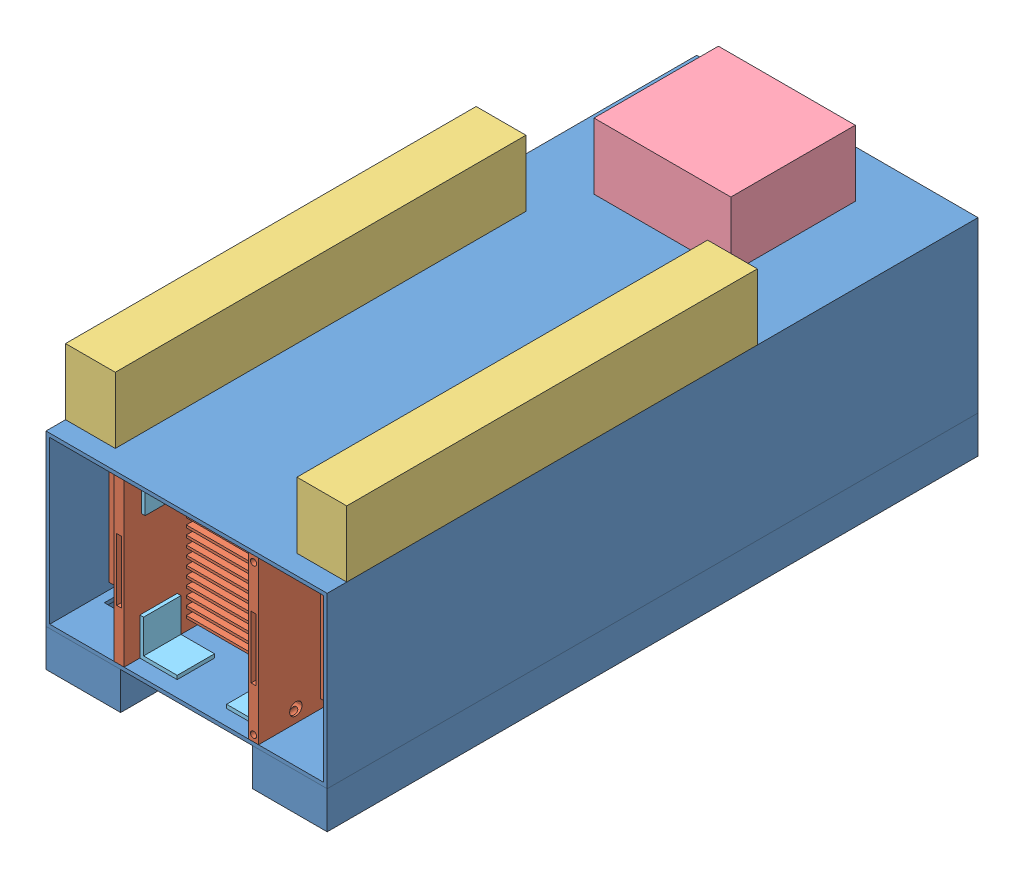
SolidWorks assembly Final_assembly, configuration Default. Lengths in mm.
Overall size (226 219 523).
11 component instances, 5 part files, 8 mates.
Components (placement in the parent):
- Final_assembly.STEP-1: Final_assembly.STEP [Default] at origin size (226 219 523)
  - Assem1.STEP-1: Assem1.STEP [Default] at (229.3481 314.0398 107.2008) size (226 193 523)
  - Fin Plate.STEP-1: Fin Plate.STEP [Default] at (279.138 249.0398 207.2008) x (0 0 1) z (-1 0 0) size (420 130 108)
  - Fin Plate.STEP-2: Fin Plate.STEP [Default] at (179.138 249.0398 627.2008) x (0 0 -1) z (1 0 0) size (420 130 108)
  - Cleanwater_Container.STEP-1: Cleanwater_Container.STEP [Default] at (134.6646 432.0398 595.4244) x (1 0 0) z (0 0 -1) size (40 53 330)
  - Cleanwater_Container.STEP-2: Cleanwater_Container.STEP [Default] at (324.0316 432.0398 297.6129) x (-1 0 0) z (0 0 1) size (40 53 330)
  - Dirtywater_Container.STEP-1: Dirtywater_Container.STEP [Default] at (238.1156 435.0398 211.5676) x (1 0 0) z (0 0 -1) size (110 53 100)
- L-Section-1: L-Section [Default] at (204.1116 379.0398 593.5422) x (-1 0 0) z (0 0 1) size (30 30 30)
- L-Section-2: L-Section [Default] at (254.1643 249.0398 593.666) size (30 30 30)
- L-Section-4: L-Section [Default] at (254.1643 379.0398 604.1937) x (1 0 0) z (0 0 -1) size (30 30 30)
- L-Section-5: L-Section [Default] at (279.138 324.0661 593.9457) x (0 1 0) z (0 0 1) size (30 30 30)
Mates (geometry in assembly coordinates):
- Coincident1: coincident: plane of Final_assembly.STEP-1/Assem1.STEP-1 through (119.3481 379.0398 627.2008) normal (0 -1 0); plane of L-Section-1 through (204.1116 379.0398 593.5422) normal (0 1 0)
- Coincident2: coincident: plane of Final_assembly.STEP-1/Fin Plate.STEP-1 through (279.138 249.0398 627.2008) normal (-1 0 0); plane of L-Section-1 through (279.138 349.0398 584.4289) normal (1 0 0)
- Coincident4: coincident: plane of Final_assembly.STEP-1/Fin Plate.STEP-2 through (179.138 249.0398 207.2008) normal (1 0 0); plane of L-Section-2 through (179.138 279.0398 584.5527) normal (-1 0 0)
- Coincident5: coincident: plane of Final_assembly.STEP-1/Assem1.STEP-1 through (119.3481 249.0398 627.2008) normal (0 1 0); plane of L-Section-2 through (254.1643 249.0398 593.666) normal (0 -1 0)
- Coincident8: coincident: plane of Final_assembly.STEP-1/Fin Plate.STEP-2 through (179.138 249.0398 207.2008) normal (1 0 0); plane of L-Section-4 through (179.138 349.0398 613.3069) normal (-1 0 0)
- Coincident9: coincident: plane of Final_assembly.STEP-1/Assem1.STEP-1 through (119.3481 379.0398 627.2008) normal (0 -1 0); plane of L-Section-4 through (254.1643 379.0398 604.1937) normal (0 1 0)
- Coincident10: coincident: plane of Final_assembly.STEP-1/Assem1.STEP-1 through (119.3481 249.0398 627.2008) normal (0 1 0); plane of L-Section-5 through (249.138 249.0398 584.8324) normal (0 -1 0)
- Coincident11: coincident: plane of Final_assembly.STEP-1/Fin Plate.STEP-1 through (279.138 249.0398 627.2008) normal (-1 0 0); plane of L-Section-5 through (279.138 324.0661 593.9457) normal (1 0 0)
